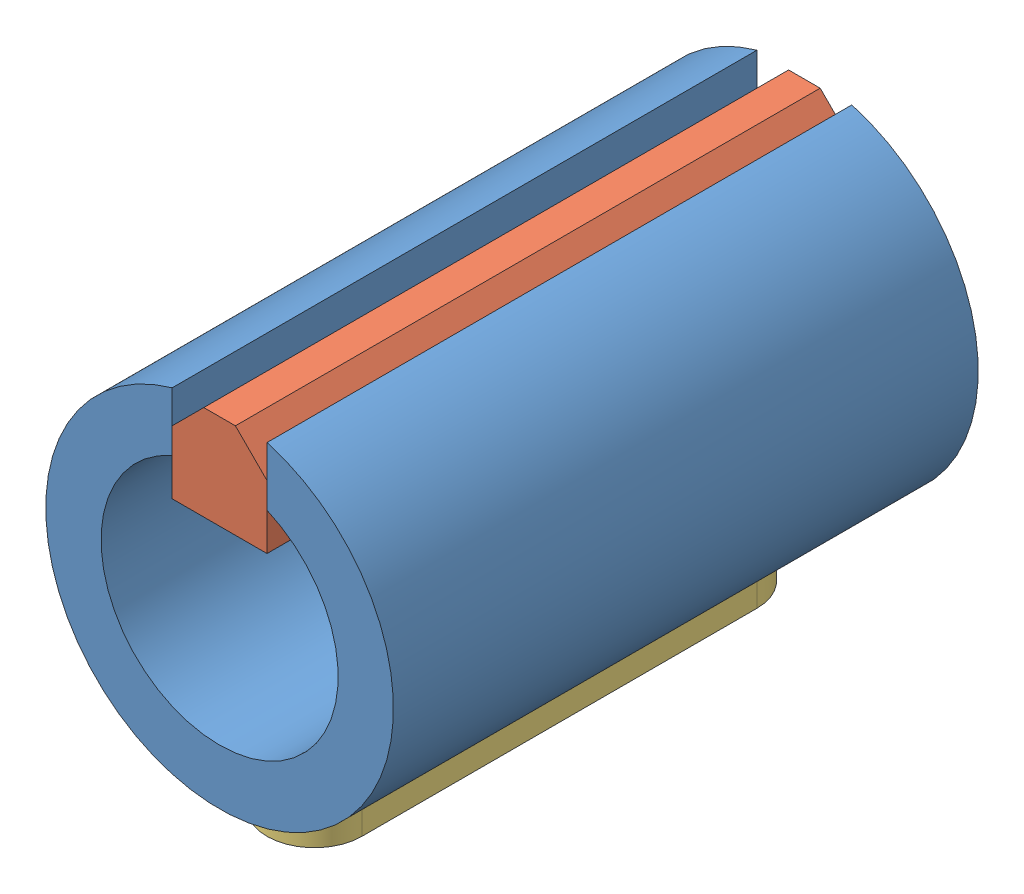
SolidWorks assembly ТП.017.03.02.00 - Втулка двигателя, configuration 00. Lengths in mm.
Overall size (22 24.58 37).
3 component instances, 3 part files, 6 mates.
Components (placement in the parent):
- ТП.017.03.02.01 - Втулка-1: ТП.017.03.02.01 - Втулка [--] at origin size (22 21.58 37)
- ТП.017.03.02.02 - Шпонка 6х6 прямая-1: ТП.017.03.02.02 - Шпонка 6х6 прямая [--] at origin size (6 6 37)
- ТП.017.03.02.03 - Шпонка 6х6 скругленная-1: ТП.017.03.02.03 - Шпонка 6х6 скругленная [--] at (0 -8 -18.5) x (0 0 1) z (0 1 0) size (31 6 6)
Mates (geometry in assembly coordinates):
- Совпадение1: coincident: plane of ТП.017.03.02.01 - Втулка-1 through (0 0 0) normal (0 0 1); plane of ТП.017.03.02.02 - Шпонка 6х6 прямая-1 through (0 3.8891 0) normal (0 0 1)
- Совпадение2: coincident: plane of ТП.017.03.02.01 - Втулка-1 through (-3 6.8739 -123.8192) normal (1 0 0); plane of ТП.017.03.02.02 - Шпонка 6х6 прямая-1 through (-3 8.3891 -45.4853) normal (-1 0 0)
- Расстояние1: distance = 3 mm: plane of ТП.017.03.02.02 - Шпонка 6х6 прямая-1 through (3 4.5 -45.4853) normal (0 -1 0); cylinder of ТП.017.03.02.01 - Втулка-1 through (0 0 -123.8192) axis (0 0 1) radius 7.5
- Совпадение3: coincident: plane of ТП.017.03.02.01 - Втулка-1 through (0 -8 -31) normal (0 -1 0); plane of ТП.017.03.02.03 - Шпонка 6х6 скругленная-1 through (0 -8 -25.4476) normal (0 1 0)
- Совпадение4: coincident: plane of ТП.017.03.02.01 - Втулка-1 through (-3 -8 -31) normal (1 0 0); plane of ТП.017.03.02.03 - Шпонка 6х6 скругленная-1 through (-3 -14 -0.4476) normal (-1 0 0)
- Концентричный1: concentric: cylinder of ТП.017.03.02.01 - Втулка-1 through (0 -8 -31) axis (0 -1 0) radius 3; cylinder of ТП.017.03.02.03 - Шпонка 6х6 скругленная-1 through (0 -14 -31) axis (0 1 0) radius 3
